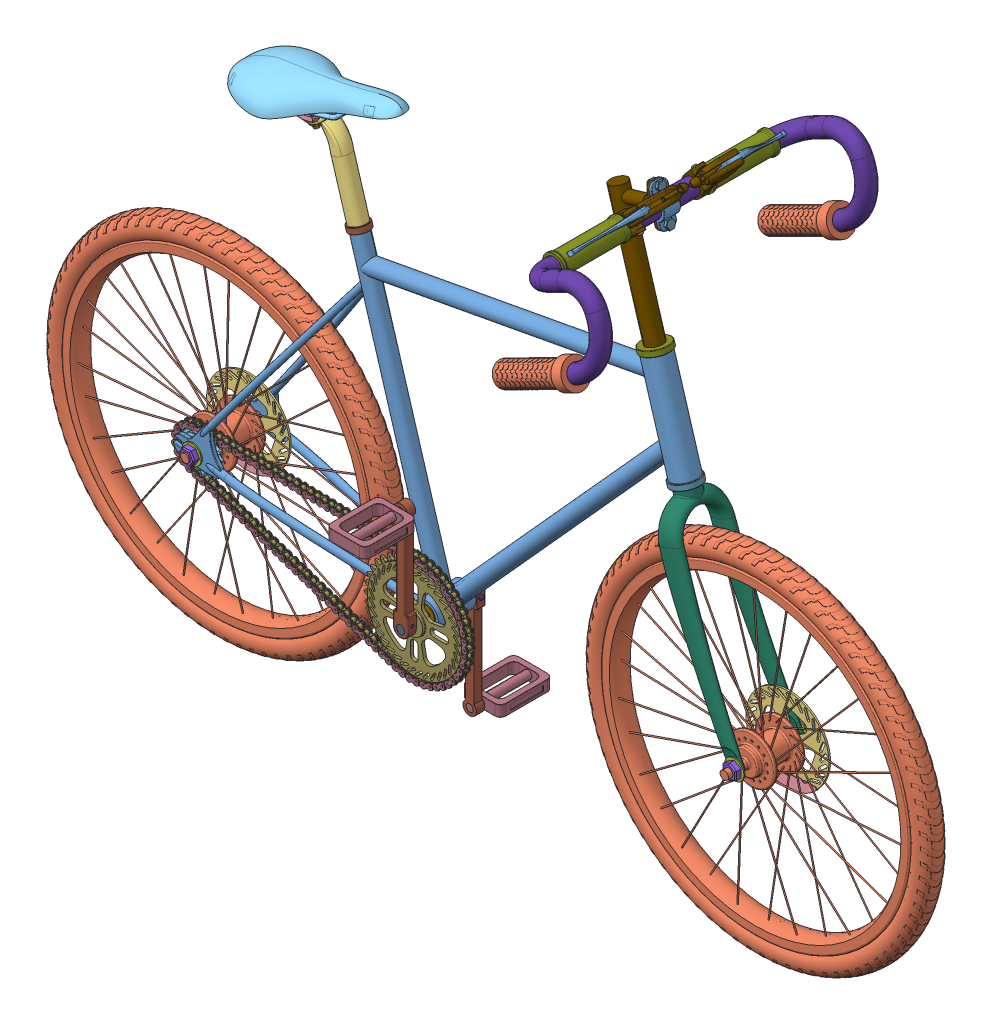
SolidWorks assembly final_bike, configuration Default. Lengths in mm.
Overall size (1608.53 1180.18 530).
171 component instances, 39 part files, 122 mates.
Components (placement in the parent):
- frame-1: frame [Default<As Machined>] at (-75.148 -269.8953 21.1634) size (885.46 618.72 128)
- wheal_break assembly_back-1: wheal_break assembly_back [Default] at (-443.9792 -198.2039 41.7807) x (1 0 0) z (0 0 -1) size (632.65 632.67 152.4)
  - final_edited-1: final_edited [Default] at (-24.9726 1.9472 38.4573) size (632.65 632.67 152.4)
  - BREAK_assembly-1: BREAK_assembly [Default] at (55.7193 -7.9409 24.4151) size (150 151 7)
    - brake-1: brake [Default] at (-80.6919 9.888 34.3622) size (150 150 3)
    - BreaK_TOP-1: BreaK_TOP [Default] at (-80.6919 9.888 35.8622) size (105.33 26 7)
  - spoket-2: spoket [Default] at (-29.24 14.7844 -56.7544) x (0 0 -1) z (0 -1 0) size (19 78.98 78.1)
    - Sprocket-1: Sprocket [18 teeth 420] at (-30.1316 4.2675 12.8372) size (15.78 78.98 78.1)
    - spoket_joint-1: spoket_joint [Default] at (-39.3316 4.2675 12.8372) x (0 0 -1) z (1 0 0) size (40 40 19)
- waser-2: waser [Default] at (-468.9517 -200.1511 83.1634) size (35 35 2)
- waser-3: waser [Default] at (-468.9517 -200.1511 -42.8366) size (35 35 2)
- nut_back-2: nut_back [Default] at (-468.9517 -200.1511 -42.8366) x (-1 0 0) z (0 0 -1) size (28.87 25 10)
- nut_back-3: nut_back [Default] at (-468.9517 -200.1511 85.1634) size (28.87 25 10)
- cover-1: cover [Default] at (-75.148 -269.8953 -12.8366) size (35 35 20)
- cover-2: cover [Default] at (-75.148 -269.8953 55.1634) x (-1 0 0) z (0 0 -1) size (35 35 20)
- axis-1: axis [Default] at (-75.148 -269.8953 -38.8366) x (-1 0 0) z (0 1 0) size (15 140 15)
- pedal_stand-1: pedal_stand [Default] at (-75.148 -269.8953 86.1634) x (-1 0 0) z (0 0 1) size (27 210.75 15)
- pedal_stand-2: pedal_stand [Default] at (-75.148 -269.8953 -23.8366) x (-1 0 0) z (0 0 -1) size (27 210.75 15)
- socket-1: socket [Default] at (-75.148 -269.8953 71.1634) size (190 189.36 12.5)
- pedal-1: pedal [Default] at (-75.148 -444.8953 -43.8366) x (0 0 -1) z (0 -1 0) size (115 71 20)
- pedal-2: pedal [Default] at (-75.148 -74.8953 106.1634) x (0 0 1) z (0 -1 0) size (115 71 20)
- fork_hub-1: fork_hub [Default] at (365.0003 128.3282 21.1634) x (-0.957571 -0.288196 0) z (-0.288196 0.957571 0) size (50 50 25)
- final_fork-1: final_fork [Default] at (-72.266 -279.4711 21.1634) size (177.98 363.04 122.79)
- wheal_break assembly_fornt-2: wheal_break assembly_fornt [Default] at (508.9638 -232.9436 42.7407) x (0 -1 0) z (0 0 -1) size (632.65 632.67 152.4)
  - final_edited-1: final_edited [Default] at (-24.9726 1.9472 38.4573) size (632.65 632.67 152.4)
  - BREAK_assembly-1: BREAK_assembly [Default] at (-34.8606 -78.7447 24.4151) x (0 -1 0) z (0 0 1) size (150 151 7)
    - brake-1: brake [Default] at (-80.6919 9.888 34.3622) size (150 150 3)
    - BreaK_TOP-1: BreaK_TOP [Default] at (-80.6919 9.888 35.8622) size (105.33 26 7)
- waser-4: waser [Default] at (507.0166 -207.9711 78.1634) size (35 35 2)
- waser-5: waser [Default] at (507.0166 -207.9711 -37.8366) size (35 35 2)
- join_upper-1: join_upper [Default] at (310.2431 310.2668 21.1634) x (-0.957571 -0.288196 0) z (-0.288196 0.957571 0) size (50 50 30)
- handle-1: handle [Default] at (384.9173 493.5908 48.2377) x (0 0 1) z (-0.892979 -0.450098 0) size (530 257.08 256.08)
  - handle_new_bar-1: handle_new_bar [Default] at (-27.0743 83.2148 34.4119) size (510 160 195)
  - break_parts2-1: break_parts2 [Default] at (-27.0743 97.9869 31.8072) x (0 -0.984808 0.173648) z (-1 0 0) size (245 91 30)
  - break_parts-1: break_parts [Default] at (-27.0743 68.4427 37.0166) x (0 0.984808 -0.173648) z (-1 0 0) size (70 20 30)
  - griper-1: griper [Default] at (212.9257 -46.7852 4.4119) x (-1 0 0) z (0 1 0) size (50 150 50)
  - griper-2: griper [Default] at (-267.0743 -46.7852 4.4119) x (-1 0 0) z (0 1 0) size (50 150 50)
- seat_stand-1: seat_stand [Default] at (-215.8096 207.5377 26.2542) x (0 0 -1) z (0.957571 0.288196 0) size (140.06 222.45 302.54)
  - stand-1: stand [Default] at (5.0908 187.7856 -27.9009) size (40.88 156.43 61.72)
  - part_2-1: part_2 [Default] at (5.0908 219.2856 -27.9009) x (0 0 -1) z (1 0 0) size (41.9 15.12 55.13)
  - seat_cover-1: seat_cover [Default] at (5.0908 217.7738 -164.6112) x (-1 0 0) z (0 0.049938 -0.998752) size (140.06 58.35 300)
  - upper_part_3-1: upper_part_3 [Default] at (5.0908 211.7856 -27.9009) x (0 0 1) z (-1 0 0) size (39.3 9.87 55.04)
  - hole_4part-1: hole_4part [Default] at (-6.9092 187.7856 -27.9009) size (12.84 3.36 16.77)
  - hole_5part-1: hole_5part [Default] at (-6.9092 218.5862 -27.9009) x (1 0 0) z (0 0 -1) size (12.84 3.15 16.57)
  - hole_5part-2: hole_5part [Default] at (17.0908 218.5862 -27.9009) x (1 0 0) z (0 0 -1) size (12.84 3.15 16.57)
  - hole_4part-3: hole_4part [Default] at (17.0908 187.7856 -27.9009) size (12.84 3.36 16.77)
  - hexalobular socket cheese head_iso-4: hexalobular socket cheese head_iso [ISO 14580 - #6 x 45 x 38 - 4.8-S] at (-6.9092 230.5356 -27.9009) x (1 0 0) z (0 0 -1) size (10 49.4 10)
  - hexalobular socket cheese head_iso-5: hexalobular socket cheese head_iso [ISO 14580 - #6 x 45 x 38 - 4.8-S] at (17.0908 230.5356 -27.9009) x (-1 0 0) z (0 0 1) size (10 49.4 10)
  - hex flange nut gradea_iso-1: hex flange nut gradea_iso [ISO - 4161 - M6 - N] at (17.0908 226.8362 -27.9009) x (1 0 0) z (0 1 0) size (14.2 14.2 6)
  - hex flange nut gradea_iso-2: hex flange nut gradea_iso [ISO - 4161 - M6 - N] at (-6.9092 226.8362 -27.9009) x (1 0 0) z (0 1 0) size (14.2 14.2 6)
- seat_stand_joint-1: seat_stand_joint [Default] at (-222.9927 221.3388 21.1634) x (0 0 -1) z (-0.288196 0.957571 0) size (35 35 60)
- chain_assembly-1: chain_assembly [Default] at (-474.5062 -201.0243 68.6634) x (0.999782 -0.020856 0) z (0 0 1) size (538.03 203.95 15.57)
  - outer_chain-1: outer_chain [Default] at (-26.4322 22.0458 5.5499) x (-0.64051 -0.76795 0) z (0 0 -1) size (24.89 12.19 11.1)
  - inner_chain-1: inner_chain [Default] at (-16.8254 30.0264 -7.2786) x (-0.872375 -0.488837 0) z (0 0 1) size (23.62 10.92 15.57)
  - inner_chain-2: inner_chain [Default] at (-32.5588 11.1625 -7.2786) x (-0.324312 -0.94595 0) z (0 0 1) size (23.62 10.92 15.57)
  - inner_chain-3: inner_chain [Default] at (-31.7092 -13.3867 -7.2786) x (0.388931 -0.921267 0) z (0 0 1) size (23.62 10.92 15.57)
  - inner_chain-4: inner_chain [Default] at (-14.7161 -31.1321 -7.2786) x (0.903012 -0.429615 0) z (0 0 1) size (23.62 10.92 15.57)
  - inner_chain-5: inner_chain [Default] at (9.2088 -39.5169 -7.2786) x (0.954894 -0.296946 0) z (0 0 1) size (23.62 10.92 15.57)
  - inner_chain-6: inner_chain [Default] at (33.4631 -47.0594 -7.2786) x (0.954894 -0.296946 0) z (0 0 1) size (23.62 10.92 15.57)
  - inner_chain-7: inner_chain [Default] at (57.7174 -54.6018 -7.2786) x (0.954894 -0.296946 0) z (0 0 1) size (23.62 10.92 15.57)
  - inner_chain-8: inner_chain [Default] at (81.9717 -62.1442 -7.2786) x (0.954894 -0.296946 0) z (0 0 1) size (23.62 10.92 15.57)
  - inner_chain-9: inner_chain [Default] at (106.2261 -69.6867 -7.2786) x (0.954894 -0.296946 0) z (0 0 1) size (23.62 10.92 15.57)
  - inner_chain-10: inner_chain [Default] at (130.4804 -77.2291 -7.2786) x (0.954894 -0.296946 0) z (0 0 1) size (23.62 10.92 15.57)
  - inner_chain-11: inner_chain [Default] at (154.7347 -84.7715 -7.2786) x (0.954894 -0.296946 0) z (0 0 1) size (23.62 10.92 15.57)
  - inner_chain-12: inner_chain [Default] at (178.9891 -92.314 -7.2786) x (0.954894 -0.296946 0) z (0 0 1) size (23.62 10.92 15.57)
  - inner_chain-13: inner_chain [Default] at (203.2434 -99.8564 -7.2786) x (0.954894 -0.296946 0) z (0 0 1) size (23.62 10.92 15.57)
  - inner_chain-14: inner_chain [Default] at (227.4977 -107.3988 -7.2786) x (0.954894 -0.296946 0) z (0 0 1) size (23.62 10.92 15.57)
  - inner_chain-15: inner_chain [Default] at (251.7521 -114.9413 -7.2786) x (0.954894 -0.296946 0) z (0 0 1) size (23.62 10.92 15.57)
  - inner_chain-16: inner_chain [Default] at (276.0064 -122.4837 -7.2786) x (0.954894 -0.296946 0) z (0 0 1) size (23.62 10.92 15.57)
  - inner_chain-17: inner_chain [Default] at (300.2607 -130.0261 -7.2786) x (0.954894 -0.296946 0) z (0 0 1) size (23.62 10.92 15.57)
  - inner_chain-18: inner_chain [Default] at (324.5151 -137.5686 -7.2786) x (0.954894 -0.296946 0) z (0 0 1) size (23.62 10.92 15.57)
  - inner_chain-19: inner_chain [Default] at (348.7694 -145.111 -7.2786) x (0.954894 -0.296946 0) z (0 0 1) size (23.62 10.92 15.57)
  - inner_chain-20: inner_chain [Default] at (373.139 -152.2322 -7.2786) x (0.973041 -0.230632 0) z (0 0 1) size (23.62 10.92 15.57)
  - inner_chain-21: inner_chain [Default] at (398.3018 -154.73 -7.2786) x (0.999393 0.034834 0) z (0 0 1) size (23.62 10.92 15.57)
  - inner_chain-22: inner_chain [Default] at (423.2297 -150.4863 -7.2786) x (0.954622 0.297821 0) z (0 0 1) size (23.62 10.92 15.57)
  - inner_chain-23: inner_chain [Default] at (446.1485 -139.8029 -7.2786) x (0.841913 0.539613 0) z (0 0 1) size (23.62 10.92 15.57)
  - inner_chain-24: inner_chain [Default] at (465.4273 -123.4403 -7.2786) x (0.669289 0.743002 0) z (0 0 1) size (23.62 10.92 15.57)
  - inner_chain-25: inner_chain [Default] at (479.6941 -102.5628 -7.2786) x (0.449034 0.893515 0) z (0 0 1) size (23.62 10.92 15.57)
  - inner_chain-26: inner_chain [Default] at (487.9334 -78.6563 -7.2786) x (0.196822 0.980439 0) z (0 0 1) size (23.62 10.92 15.57)
  - inner_chain-27: inner_chain [Default] at (489.559 -53.4221 -7.2786) x (-0.069396 0.997589 0) z (0 0 1) size (23.62 10.92 15.57)
  - inner_chain-28: inner_chain [Default] at (484.4552 -28.656 -7.2786) x (-0.330676 0.943744 0) z (0 0 1) size (23.62 10.92 15.57)
  - inner_chain-29: inner_chain [Default] at (472.9851 -6.1206 -7.2786) x (-0.568423 0.822736 0) z (0 0 1) size (23.62 10.92 15.57)
  - inner_chain-30: inner_chain [Default] at (455.9652 12.5805 -7.2786) x (-0.765717 0.643177 0) z (0 0 1) size (23.62 10.92 15.57)
  - inner_chain-31: inner_chain [Default] at (434.6065 26.1162 -7.2786) x (-0.908518 0.417845 0) z (0 0 1) size (23.62 10.92 15.57)
  - inner_chain-32: inner_chain [Default] at (410.4292 33.5233 -7.2786) x (-0.986663 0.162777 0) z (0 0 1) size (23.62 10.92 15.57)
  - inner_chain-33: inner_chain [Default] at (385.1217 35 -7.2786) x (-1 0 0) z (0 0 1) size (23.62 10.92 15.57)
  - inner_chain-34: inner_chain [Default] at (359.7216 35 -7.2786) x (-1 0 0) z (0 0 1) size (23.62 10.92 15.57)
  - inner_chain-35: inner_chain [Default] at (334.3216 35 -7.2786) x (-1 0 0) z (0 0 1) size (23.62 10.92 15.57)
  - inner_chain-36: inner_chain [Default] at (308.9216 35 -7.2786) x (-1 0 0) z (0 0 1) size (23.62 10.92 15.57)
  - inner_chain-37: inner_chain [Default] at (283.5216 35 -7.2786) x (-1 0 0) z (0 0 1) size (23.62 10.92 15.57)
  - inner_chain-38: inner_chain [Default] at (258.1216 35 -7.2786) x (-1 0 0) z (0 0 1) size (23.62 10.92 15.57)
  - inner_chain-39: inner_chain [Default] at (232.7215 35 -7.2786) x (-1 0 0) z (0 0 1) size (23.62 10.92 15.57)
  - inner_chain-40: inner_chain [Default] at (207.3215 35 -7.2786) x (-1 0 0) z (0 0 1) size (23.62 10.92 15.57)
  - inner_chain-41: inner_chain [Default] at (181.9215 35 -7.2786) x (-1 0 0) z (0 0 1) size (23.62 10.92 15.57)
  - inner_chain-42: inner_chain [Default] at (156.5215 35 -7.2786) x (-1 0 0) z (0 0 1) size (23.62 10.92 15.57)
  - inner_chain-43: inner_chain [Default] at (131.1215 35 -7.2786) x (-1 0 0) z (0 0 1) size (23.62 10.92 15.57)
  - inner_chain-44: inner_chain [Default] at (105.7215 35 -7.2786) x (-1 0 0) z (0 0 1) size (23.62 10.92 15.57)
  - inner_chain-45: inner_chain [Default] at (80.3214 35 -7.2786) x (-1 0 0) z (0 0 1) size (23.62 10.92 15.57)
  - inner_chain-46: inner_chain [Default] at (54.9214 35 -7.2786) x (-1 0 0) z (0 0 1) size (23.62 10.92 15.57)
  - inner_chain-47: inner_chain [Default] at (29.5214 35 -7.2786) x (-1 0 0) z (0 0 1) size (23.62 10.92 15.57)
  - outer_chain-2: outer_chain [Default] at (-34.3986 -1.1904 5.5499) x (0.034586 -0.999402 0) z (0 0 -1) size (24.89 12.19 11.1)
  - outer_chain-3: outer_chain [Default] at (-24.8449 -23.8204 5.5499) x (0.692067 -0.721833 0) z (0 0 -1) size (24.89 12.19 11.1)
  - outer_chain-4: outer_chain [Default] at (-2.9184 -35.7457 5.5499) x (0.954894 -0.296946 0) z (0 0 -1) size (24.89 12.19 11.1)
  - outer_chain-5: outer_chain [Default] at (21.3359 -43.2882 5.5499) x (0.954894 -0.296946 0) z (0 0 -1) size (24.89 12.19 11.1)
  - outer_chain-6: outer_chain [Default] at (45.5902 -50.8306 5.5499) x (0.954894 -0.296946 0) z (0 0 -1) size (24.89 12.19 11.1)
  - outer_chain-7: outer_chain [Default] at (69.8446 -58.373 5.5499) x (0.954894 -0.296946 0) z (0 0 -1) size (24.89 12.19 11.1)
  - outer_chain-8: outer_chain [Default] at (94.0989 -65.9155 5.5499) x (0.954894 -0.296946 0) z (0 0 -1) size (24.89 12.19 11.1)
  - outer_chain-9: outer_chain [Default] at (118.3532 -73.4579 5.5499) x (0.954894 -0.296946 0) z (0 0 -1) size (24.89 12.19 11.1)
  - outer_chain-10: outer_chain [Default] at (142.6076 -81.0003 5.5499) x (0.954894 -0.296946 0) z (0 0 -1) size (24.89 12.19 11.1)
  - outer_chain-11: outer_chain [Default] at (166.8619 -88.5428 5.5499) x (0.954894 -0.296946 0) z (0 0 -1) size (24.89 12.19 11.1)
  - outer_chain-12: outer_chain [Default] at (191.1162 -96.0852 5.5499) x (0.954894 -0.296946 0) z (0 0 -1) size (24.89 12.19 11.1)
  - outer_chain-13: outer_chain [Default] at (215.3706 -103.6276 5.5499) x (0.954894 -0.296946 0) z (0 0 -1) size (24.89 12.19 11.1)
  - outer_chain-14: outer_chain [Default] at (239.6249 -111.1701 5.5499) x (0.954894 -0.296946 0) z (0 0 -1) size (24.89 12.19 11.1)
  - outer_chain-15: outer_chain [Default] at (263.8792 -118.7125 5.5499) x (0.954894 -0.296946 0) z (0 0 -1) size (24.89 12.19 11.1)
  - outer_chain-16: outer_chain [Default] at (288.1336 -126.2549 5.5499) x (0.954894 -0.296946 0) z (0 0 -1) size (24.89 12.19 11.1)
  - outer_chain-17: outer_chain [Default] at (312.3879 -133.7974 5.5499) x (0.954894 -0.296946 0) z (0 0 -1) size (24.89 12.19 11.1)
  - outer_chain-18: outer_chain [Default] at (336.6422 -141.3398 5.5499) x (0.954894 -0.296946 0) z (0 0 -1) size (24.89 12.19 11.1)
  - outer_chain-19: outer_chain [Default] at (360.8966 -148.8821 5.5499) x (0.954898 -0.296933 0) z (0 0 -1) size (24.89 12.19 11.1)
  - outer_chain-20: outer_chain [Default] at (385.6367 -154.3239 5.5499) x (0.995109 -0.098782 0) z (0 0 -1) size (24.89 12.19 11.1)
  - outer_chain-21: outer_chain [Default] at (410.9079 -153.4431 5.5499) x (0.985816 0.167827 0) z (0 0 -1) size (24.89 12.19 11.1)
  - outer_chain-22: outer_chain [Default] at (435.047 -145.9123 5.5499) x (0.906367 0.422492 0) z (0 0 -1) size (24.89 12.19 11.1)
  - outer_chain-23: outer_chain [Default] at (456.336 -132.2674 5.5499) x (0.762414 0.64709 0) z (0 0 -1) size (24.89 12.19 11.1)
  - outer_chain-24: outer_chain [Default] at (473.26 -113.4794 5.5499) x (0.564203 0.825636 0) z (0 0 -1) size (24.89 12.19 11.1)
  - outer_chain-25: outer_chain [Default] at (484.6145 -90.8855 5.5499) x (0.32584 0.945425 0) z (0 0 -1) size (24.89 12.19 11.1)
  - outer_chain-26: outer_chain [Default] at (489.5915 -66.0936 5.5499) x (0.064287 0.997931 0) z (0 0 -1) size (24.89 12.19 11.1)
  - outer_chain-27: outer_chain [Default] at (487.8367 -40.8681 5.5499) x (-0.20184 0.979419 0) z (0 0 -1) size (24.89 12.19 11.1)
  - outer_chain-28: outer_chain [Default] at (479.475 -17.0041 5.5499) x (-0.453603 0.891204 0) z (0 0 -1) size (24.89 12.19 11.1)
  - outer_chain-29: outer_chain [Default] at (465.1016 3.8001 5.5499) x (-0.673085 0.739565 0) z (0 0 -1) size (24.89 12.19 11.1)
  - outer_chain-30: outer_chain [Default] at (445.7393 20.0638 5.5499) x (-0.844665 0.535295 0) z (0 0 -1) size (24.89 12.19 11.1)
  - outer_chain-31: outer_chain [Default] at (422.766 30.6296 5.5499) x (-0.956134 0.292929 0) z (0 0 -1) size (24.89 12.19 11.1)
  - outer_chain-32: outer_chain [Default] at (397.8178 34.7785 5.5499) x (-0.999391 0.034884 0) z (0 0 -1) size (24.89 12.19 11.1)
  - outer_chain-33: outer_chain [Default] at (372.4216 35 5.5499) x (-1 0 0) z (0 0 -1) size (24.89 12.19 11.1)
  - outer_chain-34: outer_chain [Default] at (347.0216 35 5.5499) x (-1 0 0) z (0 0 -1) size (24.89 12.19 11.1)
  - outer_chain-35: outer_chain [Default] at (321.6216 35 5.5499) x (-1 0 0) z (0 0 -1) size (24.89 12.19 11.1)
  - outer_chain-36: outer_chain [Default] at (296.2216 35 5.5499) x (-1 0 0) z (0 0 -1) size (24.89 12.19 11.1)
  - outer_chain-37: outer_chain [Default] at (270.8216 35 5.5499) x (-1 0 0) z (0 0 -1) size (24.89 12.19 11.1)
  - outer_chain-38: outer_chain [Default] at (245.4216 35 5.5499) x (-1 0 0) z (0 0 -1) size (24.89 12.19 11.1)
  - outer_chain-39: outer_chain [Default] at (220.0215 35 5.5499) x (-1 0 0) z (0 0 -1) size (24.89 12.19 11.1)
  - outer_chain-40: outer_chain [Default] at (194.6215 35 5.5499) x (-1 0 0) z (0 0 -1) size (24.89 12.19 11.1)
  - outer_chain-41: outer_chain [Default] at (169.2215 35 5.5499) x (-1 0 0) z (0 0 -1) size (24.89 12.19 11.1)
  - outer_chain-42: outer_chain [Default] at (143.8215 35 5.5499) x (-1 0 0) z (0 0 -1) size (24.89 12.19 11.1)
  - outer_chain-43: outer_chain [Default] at (118.4215 35 5.5499) x (-1 0 0) z (0 0 -1) size (24.89 12.19 11.1)
  - outer_chain-44: outer_chain [Default] at (93.0215 35 5.5499) x (-1 0 0) z (0 0 -1) size (24.89 12.19 11.1)
  - outer_chain-45: outer_chain [Default] at (67.6214 35 5.5499) x (-1 0 0) z (0 0 -1) size (24.89 12.19 11.1)
  - outer_chain-46: outer_chain [Default] at (42.2214 35 5.5499) x (-1 0 0) z (0 0 -1) size (24.89 12.19 11.1)
  - outer_chain-47: outer_chain [Default] at (16.8214 35 5.5499) x (-1 0 0) z (0 0 -1) size (24.89 12.19 11.1)
  - inner_chain-51: inner_chain [Default] at (4.1215 34.9645 -7.2786) x (-0.999984 -0.005592 0) z (0 0 1) size (23.62 10.92 15.57)
  - outer_chain-51: outer_chain [Default] at (-8.387 33.3817 5.5499) x (-0.969858 -0.243673 0) z (0 0 -1) size (24.89 12.19 11.1)
- screw-2: screw [Default] at (318.4752 581.3222 21.1634) x (0 0 1) z (-0.957571 -0.288196 0) size (17.32 15 25.5)
- screw-3: screw [Default] at (334.1429 529.2639 21.1634) x (0 0 1) z (-0.957571 -0.288196 0) size (17.32 15 25.5)
- bold-2: bold [Default] at (299.3237 575.5583 21.1634) x (0 0 -1) z (0.957571 0.288196 0) size (17.32 15 5.5)
- bold-3: bold [Default] at (314.9915 523.5 21.1634) x (0 0 -1) z (0.957571 0.288196 0) size (17.32 15 5.5)
- bell_final-2: bell_final [Default] at (254.8742 500.265 17.5778) x (-0.288196 0.957571 0) z (0 0 1) (suppressed, hidden)
- partshandle-1: partshandle [Default] at (316.7333 552.4111 96.1634) x (0.892979 0.450098 0) z (0 0 1) size (40 40 120)
- partshandle-2: partshandle [Default] at (316.7333 552.4111 -173.8366) x (0.450098 -0.892979 0) z (0 0 1) size (40 40 120)
- nut_back-4: nut_back [Default] at (507.0166 -207.9711 80.1634) x (0 1 0) z (0 0 1) size (28.87 25 10)
- nut_back-5: nut_back [Default] at (507.0166 -207.9711 -37.8366) x (-1 0 0) z (0 0 -1) size (28.87 25 10)
- goj-1: goj [Default] at (-61.648 -277.8953 -30.5866) x (-1 0 0) z (0 0 1) size (31 8 8)
- goj-3: goj [Default] at (-88.648 -261.8953 92.9134) x (1 0 0) z (0 -1 0) size (31 8 8)
- Break_cluause-1: Break_cluause [Default] at (375.5435 569.8853 108.598) x (0 0 1) z (-0.707107 0.707107 0) size (191.94 110.71 36.94)
  - Break1-1: Break1 [Default] at (-31.634 -60.6608 19.5968) size (91.08 110.68 36.94)
  - Lever-3: Lever [Default] at (-9.5632 -8.4092 30.7371) x (0.999349 0.036085 0) z (0 0 1) size (121.93 60.86 23.2)
  - nut-1: nut [Default] at (-7.8474 -11.9015 34.4063) x (1 0 0) z (0 -1 0) size (9.22 12.37 9.22)
  - nut-2: nut [Default] at (-7.8474 -11.9015 32.3499) x (0 -1 0) z (1 0 0) size (9.22 12.37 9.22)
- Break_cluause-2: Break_cluause [Default] at (329.0153 612.5205 -66.2711) x (0 0 -1) z (0.766044 -0.642788 0) size (191.94 110.71 36.94)
  - Break1-1: Break1 [Default] at (-31.634 -60.6608 19.5968) size (91.08 110.68 36.94)
  - Lever-3: Lever [Default] at (-9.5632 -8.4092 30.7371) x (0.999349 0.036085 0) z (0 0 1) size (121.93 60.86 23.2)
  - nut-1: nut [Default] at (-7.8474 -11.9015 34.4063) x (1 0 0) z (0 -1 0) size (9.22 12.37 9.22)
  - nut-2: nut [Default] at (-7.8474 -11.9015 32.3499) x (0 -1 0) z (1 0 0) size (9.22 12.37 9.22)
- hexalobular socket pan head_iso-1: hexalobular socket pan head_iso [ISO 14583 - M4 x 10 x 8.6 - 4.8-N] at (321.5653 570.3443 -41.9811) x (0.642788 0.766044 0) z (0 0 1) size (8 13.1 8)
- hexalobular socket pan head_iso-2: hexalobular socket pan head_iso [ISO 14583 - M4 x 10 x 8.6 - 4.8-N] at (334.1771 558.7877 84.3079) x (0.707107 0.707107 0) z (0 0 -1) size (8 13.1 8)
Mates (geometry in assembly coordinates):
- Concentric1: concentric aligned: cylinder of frame-1 through (-468.9517 -200.1511 55.1634) axis (0 0 -1) radius 7.5; cylinder of wheal_break assembly_back-1/final_edited-1 through (-468.9517 -200.1511 -55.0966) axis (0 0 -1) radius 7.62
- Concentric2: concentric anti-aligned: cylinder of frame-1 through (-468.9517 -200.1511 -12.8366) axis (0 0 1) radius 7.5; cylinder of wheal_break assembly_back-1/final_edited-1 through (-468.9517 -200.1511 -55.0966) axis (0 0 -1) radius 7.62
- Parallel1: parallel aligned: plane of frame-1 through (-75.148 -269.8953 21.1634) normal (1 0 0); plane of wheal_break assembly_back-1 through (-443.9792 -198.2039 41.7807) normal (1 0 0)
- Parallel2: parallel anti-aligned: plane of frame-1 through (-75.148 -269.8953 21.1634) normal (0 0 1); plane of wheal_break assembly_back-1 through (-443.9792 -198.2039 41.7807) normal (0 0 -1)
- Distance1: distance = 27 mm anti-aligned: plane of wheal_break assembly_back-1/final_edited-1 through (-450.1358 -222.8619 -6.8366) normal (0 0 -1); plane of frame-1 through (-75.148 -269.8953 -33.8366) normal (0 0 1)
- Concentric3: concentric anti-aligned: cylinder of wheal_break assembly_back-1/final_edited-1 through (-468.9517 -200.1511 -55.0966) axis (0 0 -1) radius 7.62; circle of waser-3
- Coincident4: coincident anti-aligned: plane of frame-1 through (-75.148 -269.8953 -40.8366) normal (0 0 -1); plane of waser-3 through (-468.9517 -200.1511 -40.8366) normal (0 0 1)
- Parallel3: parallel aligned: plane of frame-1 through (-75.148 -269.8953 21.1634) normal (1 0 0); plane of waser-3 through (-468.9517 -200.1511 -42.8366) normal (1 0 0)
- Concentric5: concentric aligned: cylinder of wheal_break assembly_back-1/final_edited-1 through (-468.9517 -200.1511 -55.0966) axis (0 0 -1) radius 7.62; cylinder of waser-2 through (-468.9517 -200.1511 85.1634) axis (0 0 -1) radius 7.5
- Coincident6: coincident anti-aligned: plane of frame-1 through (-75.148 -269.8953 83.1634) normal (0 0 1); plane of waser-2 through (-468.9517 -200.1511 83.1634) normal (0 0 -1)
- Parallel4: parallel aligned: plane of frame-1 through (-75.148 -269.8953 21.1634) normal (1 0 0); plane of waser-2 through (-468.9517 -200.1511 83.1634) normal (1 0 0)
- Concentric7: concentric anti-aligned: cylinder of wheal_break assembly_back-1/final_edited-1 through (-468.9517 -200.1511 -55.0966) axis (0 0 -1) radius 7.62; cylinder of nut_back-2 through (-468.9517 -200.1511 -52.8366) axis (0 0 1) radius 7.5
- Coincident10: coincident anti-aligned: plane of waser-3 through (-468.9517 -200.1511 -42.8366) normal (0 0 -1); plane of nut_back-2 through (-468.9517 -200.1511 -42.8366) normal (0 0 1)
- Parallel6: parallel anti-aligned: plane of waser-3 through (-468.9517 -200.1511 -42.8366) normal (1 0 0); plane of nut_back-2 through (-468.9517 -200.1511 -42.8366) normal (-1 0 0)
- Concentric8: concentric aligned: cylinder of wheal_break assembly_back-1/final_edited-1 through (-468.9517 -200.1511 -55.0966) axis (0 0 -1) radius 7.62; cylinder of nut_back-3 through (-468.9517 -200.1511 95.1634) axis (0 0 -1) radius 7.5
- Coincident12: coincident anti-aligned: plane of waser-2 through (-468.9517 -200.1511 85.1634) normal (0 0 1); plane of nut_back-3 through (-468.9517 -200.1511 85.1634) normal (0 0 -1)
- Parallel7: parallel aligned: plane of waser-2 through (-468.9517 -200.1511 83.1634) normal (1 0 0); plane of nut_back-3 through (-468.9517 -200.1511 85.1634) normal (1 0 0)
- Concentric9: concentric aligned: cylinder of frame-1 through (-75.148 -269.8953 55.1634) axis (0 0 -1) radius 17.5; cylinder of cover-1 through (-75.148 -269.8953 -7.8366) axis (0 0 -1) radius 17.5
- Coincident13: coincident aligned: plane of frame-1 through (-75.148 -269.8953 -12.8366) normal (0 0 -1); plane of cover-1 through (-75.148 -269.8953 -12.8366) normal (0 0 -1)
- Parallel8: parallel aligned: plane of frame-1 through (-75.148 -269.8953 21.1634) normal (1 0 0); plane of cover-1 through (-75.148 -269.8953 -12.8366) normal (1 0 0)
- Concentric10: concentric anti-aligned: cylinder of frame-1 through (-75.148 -269.8953 55.1634) axis (0 0 -1) radius 17.5; cylinder of cover-2 through (-75.148 -269.8953 50.1634) axis (0 0 1) radius 17.5
- Coincident15: coincident aligned: plane of frame-1 through (-75.148 -269.8953 55.1634) normal (0 0 1); plane of cover-2 through (-75.148 -269.8953 55.1634) normal (0 0 1)
- Parallel13: parallel aligned: plane of cover-2 through (-75.148 -269.8953 55.1634) normal (-1 0 0); plane of axis-1 through (-75.148 -269.8953 -38.8366) normal (-1 0 0)
- Parallel14: parallel aligned: plane of cover-2 through (-75.148 -269.8953 55.1634) normal (-1 0 0); plane of axis-1 through (-75.148 -269.8953 -38.8366) normal (-1 0 0)
- Parallel15: parallel anti-aligned: plane of frame-1 through (-75.148 -269.8953 21.1634) normal (1 0 0); plane of cover-2 through (-75.148 -269.8953 55.1634) normal (-1 0 0)
- Parallel16: parallel anti-aligned: plane of frame-1 through (-75.148 -269.8953 21.1634) normal (1 0 0); plane of axis-1 through (-75.148 -269.8953 -38.8366) normal (-1 0 0)
- Concentric12: concentric aligned: cylinder of cover-1 through (-75.148 -269.8953 7.1634) axis (0 0 -1) radius 7.5; cylinder of axis-1 through (-75.148 -269.8953 -38.8366) axis (0 0 -1) radius 7.5
- Distance6: distance = 46 mm aligned: plane of axis-1 through (-75.148 -269.8953 101.1634) normal (0 0 1); plane of cover-2 through (-75.148 -269.8953 55.1634) normal (0 0 1)
- Parallel17: parallel anti-aligned: plane of frame-1 through (-75.148 -269.8953 21.1634) normal (1 0 0); plane of axis-1 through (-75.148 -269.8953 -38.8366) normal (-1 0 0)
- Concentric13: concentric aligned: cylinder of axis-1 through (-75.148 -269.8953 -38.8366) axis (0 0 -1) radius 7.5; cylinder of pedal_stand-1 through (-75.148 -269.8953 101.1634) axis (0 0 -1) radius 7.5
- Coincident26: coincident aligned: plane of axis-1 through (-75.148 -269.8953 101.1634) normal (0 0 1); plane of pedal_stand-1 through (-75.148 -269.8953 101.1634) normal (0 0 1)
- Concentric14: concentric anti-aligned: cylinder of axis-1 through (-75.148 -269.8953 -38.8366) axis (0 0 -1) radius 7.5; cylinder of pedal_stand-2 through (-75.148 -269.8953 -38.8366) axis (0 0 1) radius 7.5
- Coincident27: coincident aligned: plane of axis-1 through (-75.148 -277.3953 -38.8366) normal (0 0 -1); plane of pedal_stand-2 through (-75.148 -269.8953 -38.8366) normal (0 0 -1)
- Parallel18: parallel aligned: plane of axis-1 through (-75.148 -269.8953 -38.8366) normal (-1 0 0); plane of pedal_stand-1 through (-75.148 -269.8953 86.1634) normal (-1 0 0)
- Parallel19: parallel aligned: plane of axis-1 through (-75.148 -269.8953 -38.8366) normal (-1 0 0); plane of pedal_stand-2 through (-75.148 -269.8953 -23.8366) normal (-1 0 0)
- Concentric15: concentric anti-aligned: cylinder of axis-1 through (-75.148 -269.8953 -38.8366) axis (0 0 -1) radius 7.5; cylinder of socket-1 through (-75.148 -269.8953 68.6634) axis (0 0 1) radius 7.5
- Distance7: distance = 5 mm anti-aligned: plane of socket-1 through (-75.148 -269.8953 81.1634) normal (0 0 1); plane of pedal_stand-1 through (-75.148 -269.8953 86.1634) normal (0 0 -1)
- Parallel20: parallel anti-aligned: plane of axis-1 through (-75.148 -269.8953 -38.8366) normal (-1 0 0); plane of socket-1 through (-75.148 -269.8953 71.1634) normal (1 0 0)
- Concentric16: concentric anti-aligned: cylinder of pedal_stand-2 through (-75.148 -454.8953 -38.8366) axis (0 0 1) radius 6.5; cylinder of pedal-1 through (-75.148 -454.8953 -23.8366) axis (0 0 -1) radius 6.5
- Coincident32: coincident aligned: plane of pedal_stand-2 through (-75.148 -269.8953 -23.8366) normal (0 0 1); plane of pedal-1 through (-75.148 -454.8953 -23.8366) normal (0 0 1)
- Concentric17: concentric anti-aligned: cylinder of pedal_stand-1 through (-75.148 -84.8953 101.1634) axis (0 0 -1) radius 6.5; cylinder of pedal-2 through (-75.148 -84.8953 86.1634) axis (0 0 1) radius 6.5
- Coincident33: coincident aligned: plane of pedal_stand-1 through (-75.148 -269.8953 86.1634) normal (0 0 -1); plane of pedal-2 through (-75.148 -84.8953 86.1634) normal (0 0 -1)
- Perpendicular2: perpendicular: plane of pedal_stand-1 through (-75.148 -269.8953 86.1634) normal (-1 0 0); plane of pedal-2 through (-75.148 -74.8953 106.1634) normal (0 0 1)
- Coincident38: coincident aligned: plane of pedal_stand-1 through (-75.148 -269.8953 86.1634) normal (-1 0 0); plane of pedal-2 through (-75.148 -74.8953 106.1634) normal (-1 0 0)
- Coincident39: coincident anti-aligned: plane of pedal_stand-2 through (-75.148 -269.8953 -23.8366) normal (-1 0 0); plane of pedal-1 through (-75.148 -444.8953 -43.8366) normal (1 0 0)
- Concentric18: concentric anti-aligned: cylinder of frame-1 through (359.2364 147.4797 21.1634) axis (-0.288196 0.957571 0) radius 17.5; cylinder of fork_hub-1 through (357.7954 152.2675 21.1634) axis (0.288196 -0.957571 0) radius 17
- Coincident40: coincident anti-aligned: plane of frame-1 through (359.2364 147.4797 21.1634) normal (0.288196 -0.957571 0); plane of fork_hub-1 through (359.2364 147.4797 21.1634) normal (-0.288196 0.957571 0)
- Parallel21: parallel aligned: plane of frame-1 through (-75.148 -269.8953 21.1634) normal (0 0 1); plane of fork_hub-1 through (365.0003 128.3282 21.1634) normal (0 0 1)
- Concentric19: concentric anti-aligned: cylinder of fork_hub-1 through (362.1184 137.9039 21.1634) axis (0.288196 -0.957571 0) radius 17.5; cylinder of final_fork-1 through (366.4413 123.5404 21.1634) axis (-0.288196 0.957571 0) radius 18.5
- Coincident42: coincident anti-aligned: plane of fork_hub-1 through (362.1184 137.9039 21.1634) normal (0.288196 -0.957571 0); plane of final_fork-1 through (362.1184 137.9039 21.1634) normal (-0.288196 0.957571 0)
- Parallel22: parallel aligned: plane of fork_hub-1 through (365.0003 128.3282 21.1634) normal (0 0 1); plane of final_fork-1 through (-72.266 -279.4711 21.1634) normal (0 0 1)
- Concentric20: concentric anti-aligned: cylinder of final_fork-1 through (507.0166 -207.9711 21.1634) axis (0 0 1) radius 5.5; cylinder of wheal_break assembly_fornt-2/final_edited-1 through (507.0166 -207.9711 -54.1366) axis (0 0 -1) radius 7.62
- Concentric21: concentric aligned: cylinder of final_fork-1 through (507.0166 -207.9711 21.1634) axis (0 0 -1) radius 5.5; cylinder of wheal_break assembly_fornt-2/final_edited-1 through (507.0166 -207.9711 -54.1366) axis (0 0 -1) radius 7.62
- Distance8: distance = 11 mm anti-aligned: plane of wheal_break assembly_fornt-2/final_edited-1 through (499.3966 -207.9711 60.1634) normal (0 0 1); plane of final_fork-1 through (1667.2787 510.3486 71.1634) normal (0 0 -1)
- Parallel24: parallel anti-aligned: plane of final_fork-1 through (-72.266 -279.4711 21.1634) normal (0 0 1); plane of wheal_break assembly_fornt-2 through (508.9638 -232.9436 42.7407) normal (0 0 -1)
- Parallel25: parallel anti-aligned: plane of final_fork-1 through (-72.266 -279.4711 21.1634) normal (1 0 0); plane of wheal_break assembly_fornt-2 through (508.9638 -232.9436 42.7407) normal (-1 0 0)
- Concentric22: concentric aligned: cylinder of wheal_break assembly_fornt-2/final_edited-1 through (507.0166 -207.9711 -54.1366) axis (0 0 -1) radius 7.62; cylinder of waser-4 through (507.0166 -207.9711 80.1634) axis (0 0 -1) radius 7.5
- Coincident48: coincident anti-aligned: plane of final_fork-1 through (1667.2787 510.3486 78.1634) normal (0 0 1); plane of waser-4 through (507.0166 -207.9711 78.1634) normal (0 0 -1)
- Concentric23: concentric aligned: cylinder of wheal_break assembly_fornt-2/final_edited-1 through (507.0166 -207.9711 -54.1366) axis (0 0 -1) radius 7.62; cylinder of waser-5 through (507.0166 -207.9711 -35.8366) axis (0 0 -1) radius 7.5
- Coincident49: coincident anti-aligned: plane of final_fork-1 through (1667.2787 510.3486 -35.8366) normal (0 0 -1); plane of waser-5 through (507.0166 -207.9711 -35.8366) normal (0 0 1)
- Parallel27: parallel aligned: plane of frame-1 through (-75.148 -269.8953 21.1634) normal (1 0 0); plane of waser-4 through (507.0166 -207.9711 78.1634) normal (1 0 0)
- Parallel28: parallel aligned: plane of frame-1 through (-75.148 -269.8953 21.1634) normal (1 0 0); plane of waser-5 through (507.0166 -207.9711 -37.8366) normal (1 0 0)
- Concentric24: concentric anti-aligned: cylinder of frame-1 through (359.2364 147.4797 21.1634) axis (-0.288196 0.957571 0) radius 17.5; cylinder of join_upper-1 through (307.3611 319.8425 21.1634) axis (0.288196 -0.957571 0) radius 17.5
- Coincident50: coincident anti-aligned: plane of frame-1 through (307.3611 319.8425 21.1634) normal (-0.288196 0.957571 0); plane of join_upper-1 through (307.3611 319.8425 21.1634) normal (0.288196 -0.957571 0)
- Concentric25: concentric aligned: cylinder of join_upper-1 through (301.5972 338.9939 21.1634) axis (0.288196 -0.957571 0) radius 12.5; cylinder of handle-1/break_parts2-1 through (301.5972 338.9939 21.1634) axis (0.288196 -0.957571 0) radius 12.5
- Coincident51: coincident anti-aligned: plane of join_upper-1 through (304.4791 329.4182 21.1634) normal (-0.288196 0.957571 0); plane of handle-1/break_parts2-1 through (304.4791 329.4182 21.1634) normal (0.288196 -0.957571 0)
- Coincident52: coincident aligned: plane of frame-1 through (-75.148 -269.8953 21.1634) normal (0 0 1); plane of join_upper-1 through (310.2431 310.2668 21.1634) normal (0 0 1)
- Parallel29: parallel aligned: plane of join_upper-1 through (310.2431 310.2668 21.1634) normal (0 0 1); plane of handle-1 through (384.9173 493.5908 48.2377) normal (0 0 1)
- Concentric26: concentric aligned: cylinder of frame-1 through (-228.7566 240.4902 21.1634) axis (0.288196 -0.957571 0) radius 11.5; cylinder of seat_stand_joint-1 through (-228.7566 240.4902 21.1634) axis (0.288196 -0.957571 0) radius 11.5
- Coincident53: coincident anti-aligned: plane of frame-1 through (-228.7566 240.4902 21.1634) normal (-0.288196 0.957571 0); plane of seat_stand_joint-1 through (-228.7566 240.4902 21.1634) normal (0.288196 -0.957571 0)
- Concentric27: concentric anti-aligned: cylinder of seat_stand-1/stand-1 through (-231.6385 250.0659 21.1634) axis (-0.288196 0.957571 0) radius 13; cylinder of seat_stand_joint-1 through (-240.2844 278.7931 21.1634) axis (0.288196 -0.957571 0) radius 13
- Coincident54: coincident anti-aligned: plane of seat_stand-1/stand-1 through (-231.6385 250.0659 21.1634) normal (0.288196 -0.957571 0); plane of seat_stand_joint-1 through (-231.6385 250.0659 21.1634) normal (-0.288196 0.957571 0)
- Parallel30: parallel anti-aligned: plane of frame-1 through (-75.148 -269.8953 21.1634) normal (0 0 1); plane of seat_stand_joint-1 through (-222.9927 221.3388 21.1634) normal (0 0 -1)
- Parallel31: parallel aligned: plane of seat_stand-1 through (-215.8096 207.5377 26.2542) normal (0 0 -1); plane of seat_stand_joint-1 through (-222.9927 221.3388 21.1634) normal (0 0 -1)
- Coincident55: coincident aligned: plane of socket-1 through (-75.148 -269.8953 68.6634) normal (0 0 -1); plane of chain_assembly-1/outer_chain-1 through (-500.4728 -178.432 68.6634) normal (0 0 -1)
- Coincident56: coincident: line of wheal_break assembly_back-1/spoket-2/Sprocket-1 through (-506.229 -197.9708 70.8205) axis (0 0 -1); cylinder of chain_assembly-1/outer_chain-2 through (-509.0093 -195.1476 64.701) axis (0 0 1) radius 3.9624
- Concentric34: concentric aligned: cylinder of socket-1 through (7.2716 -233.7427 68.6634) axis (0 0 1) radius 5; cylinder of chain_assembly-1/outer_chain-28 through (7.2716 -233.7427 64.701) axis (0 0 1) radius 3.9624
- Concentric36: concentric aligned: cylinder of handle-1/break_parts-1 through (304.1116 576.9993 21.1634) axis (0.957571 0.288196 0) radius 5; cylinder of screw-2 through (294.5359 574.1173 21.1634) axis (0.957571 0.288196 0) radius 5
- Coincident59: coincident aligned: circle of handle-1/break_parts-1; cylinder of screw-3 through (310.2036 522.059 21.1634) axis (0.957571 0.288196 0) radius 5
- Parallel32: parallel aligned: plane of screw-3 through (334.1429 529.2639 21.1634) normal (0 0 1)
- Parallel33: parallel aligned: plane of screw-2 through (318.4752 581.3222 21.1634) normal (0 0 1)
- Concentric37: concentric aligned: cylinder of screw-2 through (294.5359 574.1173 21.1634) axis (0.957571 0.288196 0) radius 5; cylinder of bold-2 through (299.3237 575.5583 21.1634) axis (0.957571 0.288196 0) radius 5
- Coincident63: coincident anti-aligned: plane of handle-1/break_parts-1 through (311.4343 587.3671 36.1634) normal (0.957571 0.288196 0); plane of screw-2 through (313.6873 579.8812 21.1634) normal (-0.957571 -0.288196 0)
- Coincident64: coincident anti-aligned: plane of handle-1/break_parts2-1 through (301.8586 584.4851 36.1634) normal (-0.957571 -0.288196 0); plane of bold-2 through (304.1116 576.9993 21.1634) normal (0.957571 0.288196 0)
- Coincident65: coincident aligned: cylinder of screw-3 through (310.2036 522.059 21.1634) axis (0.957571 0.288196 0) radius 5; circle of bold-3
- Coincident66: coincident anti-aligned: plane of handle-1/break_parts-1 through (331.6081 520.3371 36.1634) normal (0.957571 0.288196 0); plane of screw-3 through (329.3551 527.823 21.1634) normal (-0.957571 -0.288196 0)
- Coincident67: coincident anti-aligned: plane of handle-1/break_parts2-1 through (322.0323 517.4551 36.1634) normal (-0.957571 -0.288196 0); plane of bold-3 through (319.7794 524.941 21.1634) normal (0.957571 0.288196 0)
- Parallel34: parallel anti-aligned: plane of screw-2 through (318.4752 581.3222 21.1634) normal (0 0 1); plane of bold-2 through (299.3237 575.5583 21.1634) normal (0 0 -1)
- Parallel35: parallel anti-aligned: plane of screw-3 through (334.1429 529.2639 21.1634) normal (0 0 1); plane of bold-3 through (314.9915 523.5 21.1634) normal (0 0 -1)
- Concentric39: concentric aligned: cylinder of handle-1/break_parts2-1 through (238.194 549.6596 21.1634) axis (0.288196 -0.957571 0) radius 15; cylinder of bell_final-2/base-1 through (252.6038 501.7811 21.1634) axis (0.288196 -0.957571 0) radius 15
- Distance9: distance = 150 mm anti-aligned: plane of join_upper-1 through (304.4791 329.4182 21.1634) normal (-0.288196 0.957571 0); plane of bell_final-2/base-1 through (261.2497 473.0539 21.1634) normal (0.288196 -0.957571 0)
- Parallel36: parallel aligned: plane of bell_final-2 through (254.8742 500.265 17.5778) normal (0 0 1)
- Concentric40: concentric aligned: cylinder of handle-1/handle_new_bar-1 through (316.7333 552.4111 21.1634) axis (0 0 -1) radius 15; cylinder of partshandle-1 through (316.7333 552.4111 216.1634) axis (0 0 -1) radius 15
- Concentric41: concentric aligned: cylinder of handle-1/handle_new_bar-1 through (316.7333 552.4111 21.1634) axis (0 0 -1) radius 15; cylinder of partshandle-2 through (316.7333 552.4111 -53.8366) axis (0 0 -1) radius 15
- Parallel37: parallel anti-aligned: plane of handle-1 through (384.9173 493.5908 48.2377) normal (-0.892979 -0.450098 0); plane of partshandle-1 through (316.7333 552.4111 96.1634) normal (0.892979 0.450098 0)
- Parallel38: parallel anti-aligned: plane of handle-1 through (384.9173 493.5908 48.2377) normal (-0.892979 -0.450098 0); plane of partshandle-2 through (316.7333 552.4111 -173.8366) normal (0.892979 0.450098 0)
- Distance10: distance = 60 mm anti-aligned: plane of handle-1/break_parts-1 through (316.7333 552.4111 6.1634) normal (0 0 -1); plane of partshandle-2 through (316.7333 552.4111 -53.8366) normal (0 0 1)
- Distance11: distance = 60 mm anti-aligned: plane of handle-1/break_parts-1 through (316.7333 552.4111 36.1634) normal (0 0 1); plane of partshandle-1 through (325.7353 534.5515 96.1634) normal (0 0 -1)
- Concentric43: concentric aligned: cylinder of wheal_break assembly_fornt-2/final_edited-1 through (507.0166 -207.9711 -54.1366) axis (0 0 -1) radius 7.62; cylinder of nut_back-4 through (507.0166 -207.9711 90.1634) axis (0 0 -1) radius 7.5
- Coincident68: coincident anti-aligned: plane of waser-4 through (507.0166 -207.9711 80.1634) normal (0 0 1); plane of nut_back-4 through (507.0166 -207.9711 80.1634) normal (0 0 -1)
- Parallel39: parallel aligned: plane of nut_back-4 through (507.0166 -207.9711 80.1634) normal (0 1 0)
- Concentric44: concentric anti-aligned: cylinder of wheal_break assembly_fornt-2/final_edited-1 through (507.0166 -207.9711 -54.1366) axis (0 0 -1) radius 7.62; cylinder of nut_back-5 through (507.0166 -207.9711 -47.8366) axis (0 0 1) radius 7.5
- Coincident70: coincident anti-aligned: plane of waser-5 through (507.0166 -207.9711 -37.8366) normal (0 0 -1); plane of nut_back-5 through (507.0166 -207.9711 -37.8366) normal (0 0 1)
- Parallel40: parallel aligned: plane of nut_back-5 through (507.0166 -207.9711 -37.8366) normal (0 1 0)
- Concentric45: concentric anti-aligned: cylinder of pedal_stand-2 through (-61.648 -277.8953 -30.5866) axis (-1 0 0) radius 3; cylinder of goj-1 through (-88.648 -277.8953 -30.5866) axis (1 0 0) radius 3
- Coincident71: coincident anti-aligned: plane of pedal_stand-2 through (-61.648 -269.8953 -38.8366) normal (1 0 0); plane of goj-1 through (-61.648 -277.8953 -30.5866) normal (-1 0 0)
- Parallel43: parallel anti-aligned: plane of goj-1 through (-61.648 -277.8953 -30.5866) normal (0 -1 0); plane of axis-1 through (-75.148 -269.8953 -38.8366) normal (0 1 0)
- Concentric47: concentric aligned: cylinder of pedal_stand-1 through (-61.648 -261.8953 92.9134) axis (-1 0 0) radius 3; cylinder of goj-3 through (-61.648 -261.8953 92.9134) axis (-1 0 0) radius 3
- Coincident76: coincident anti-aligned: plane of pedal_stand-1 through (-88.648 -269.8953 101.1634) normal (-1 0 0); plane of goj-3 through (-88.648 -261.8953 92.9134) normal (1 0 0)
- Parallel44: parallel anti-aligned: plane of axis-1 through (-75.148 -269.8953 -38.8366) normal (0 1 0); plane of goj-3 through (-88.648 -261.8953 92.9134) normal (0 -1 0)
- Concentric49: concentric aligned: cylinder of handle-1/handle_new_bar-1 through (316.7333 552.4111 21.1634) axis (0 0 -1) radius 15; cylinder of Break_cluause-1/Break1-1 through (316.7333 552.4111 137.6314) axis (0 0 -1) radius 13.8303
- Distance12: distance = 40 mm anti-aligned: plane of Break_cluause-1/Break1-1 through (290.6547 552.4111 76.1634) normal (0 0 -1); plane of handle-1/break_parts-1 through (316.7333 552.4111 36.1634) normal (0 0 1)
- Angle1: planar angle = 0.785398 rad: plane of assembly through (0 0 0) normal (0 1 0); plane of assembly; plane of Break_cluause-1 through (375.5435 569.8853 108.598) normal (0.707107 0.707107 0)
- Concentric50: concentric anti-aligned: cylinder of handle-1/handle_new_bar-1 through (316.7333 552.4111 21.1634) axis (0 0 -1) radius 15; cylinder of Break_cluause-2/Break1-1 through (316.7333 552.4111 -95.3046) axis (0 0 1) radius 13.8303
- Distance13: distance = 40 mm anti-aligned: plane of Break_cluause-2/Break1-1 through (319.0062 526.4317 -33.8366) normal (0 0 1); plane of handle-1/break_parts-1 through (316.7333 552.4111 6.1634) normal (0 0 -1)
- Angle2: planar angle = 0.872665 rad: plane of assembly through (0 0 0) normal (0 1 0); plane of assembly; plane of Break_cluause-2 through (329.0153 612.5205 -66.2711) normal (0.766044 -0.642788 0)
- Concentric52: concentric anti-aligned: cylinder of Break_cluause-2/Break1-1 through (324.264 568.0798 -41.9811) axis (-0.766044 0.642788 0) radius 2.3051; cylinder of hexalobular socket pan head_iso-1 through (321.5653 570.3443 -41.9811) axis (0.766044 -0.642788 0) radius 2.35
- Coincident77: coincident anti-aligned: plane of Break_cluause-2/Break1-1 through (313.9048 576.7722 -41.9811) normal (-0.766044 0.642788 0); plane of hexalobular socket pan head_iso-1 through (315.4154 578.5724 -41.9811) normal (0.766044 -0.642788 0)
- Concentric53: concentric anti-aligned: cylinder of Break_cluause-1/Break1-1 through (331.686 561.2788 84.3079) axis (0.707107 -0.707107 0) radius 2.3051; cylinder of hexalobular socket pan head_iso-2 through (334.1771 558.7877 84.3079) axis (-0.707107 0.707107 0) radius 2.35
- Coincident78: coincident anti-aligned: plane of Break_cluause-1/Break1-1 through (341.2482 551.7166 84.3079) normal (0.707107 -0.707107 0); plane of hexalobular socket pan head_iso-2 through (342.9099 553.3783 84.3079) normal (-0.707107 0.707107 0)
- Parallel46: parallel anti-aligned: plane of hexalobular socket pan head_iso-2 through (334.1771 558.7877 84.3079) normal (0 0 -1)
- Parallel47: parallel aligned: plane of hexalobular socket pan head_iso-1 through (321.5653 570.3443 -41.9811) normal (0 0 1)
